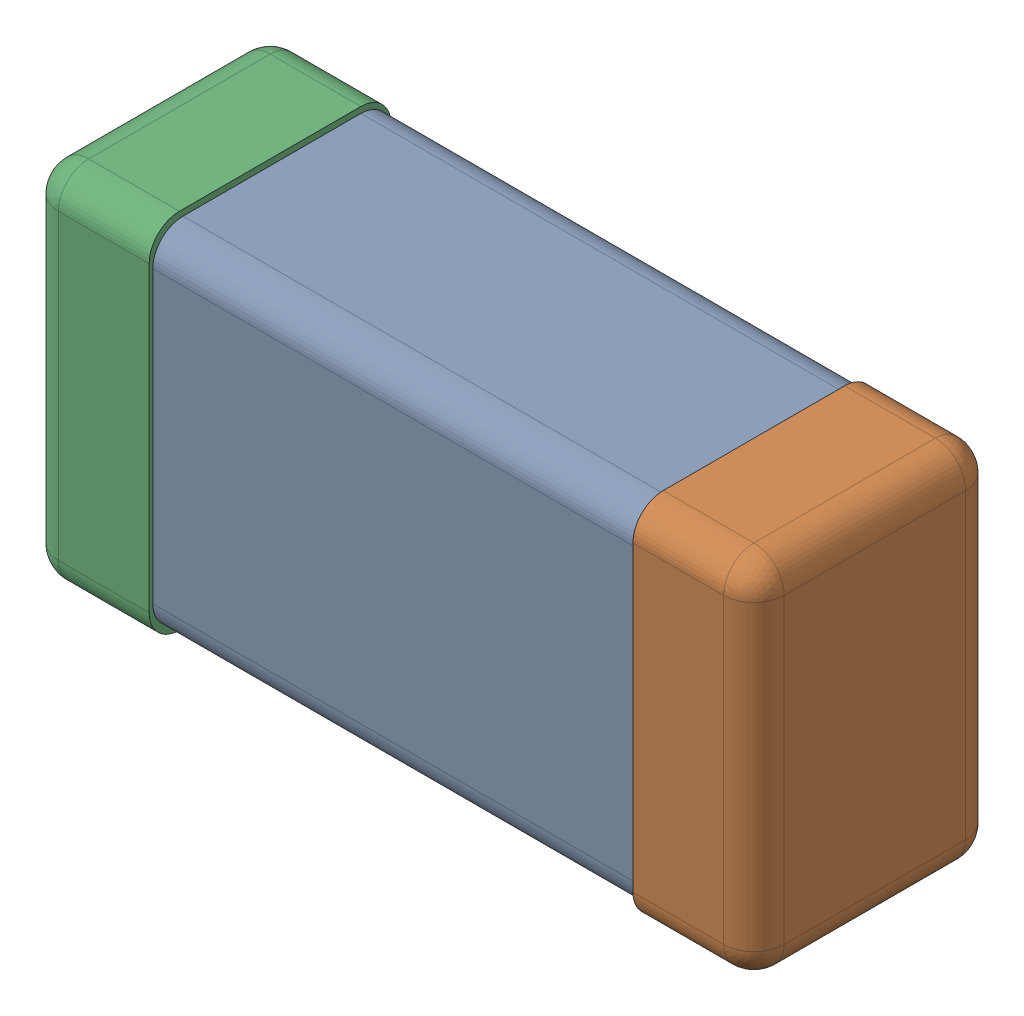
SolidWorks assembly C0201_020_32, configuration Standard. Lengths in mm.
Overall size (0.6 0.3 0.2).
4 component instances, 3 part files, 0 mates.
Components (placement in the parent):
- C0201_020_33-1: C0201_020_33 [Standard] at origin size (0.6 0.3 0.2)
  - Part 3_2-1: Part 3_2 [Standard] at (0 0 -7.3015) size (0.5 0.29 0.2)
  - Part 2_2-1: Part 2_2 [Standard] at (0 0 -7.3) size (0.1 0.3 0.2)
  - Part 1_2-1: Part 1_2 [Standard] at (0 0 -7.3) size (0.1 0.3 0.2)
